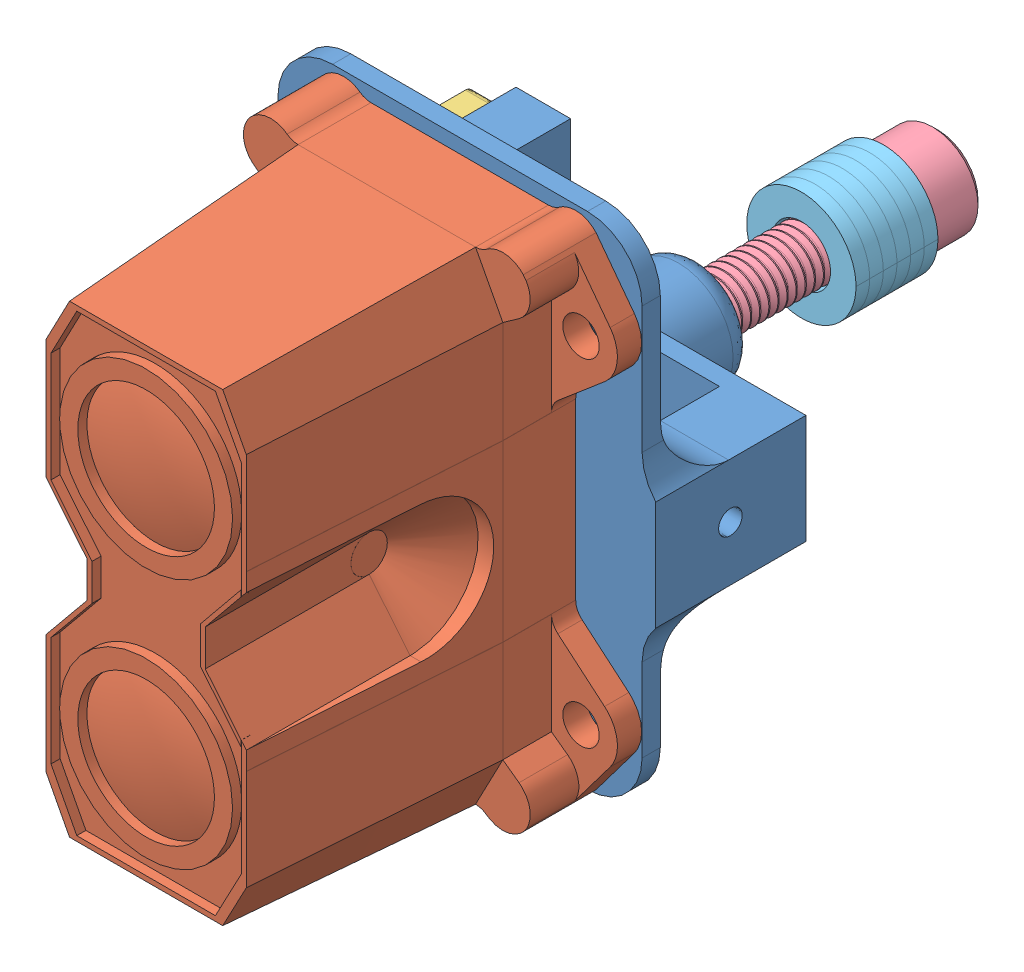
SolidWorks assembly lidar_assembly, configuration Default. Lengths in mm.
Overall size (46.37 55.51 87.17).
10 component instances, 5 part files, 7 mates.
Components (placement in the parent):
- lidar_mount-1: lidar_mount [Default] at (57.1287 41.2951 14.349) size (41.87 55 26.5)
- Garmin LIDAR-Lite V3HP-1: Garmin LIDAR-Lite V3HP [Default] at (77.1287 68.2951 16.3924) x (-1 0 0) z (0 1 0) size (44.51 34.67 55.01)
- SG90 - Micro Servo 9g - Tower Pro.1-2: SG90 - Micro Servo 9g - Tower Pro.1 [Peça] at (71.9287 71.6451 8.149) x (0 1 0) z (0 0 1) size (32.1 29.95 12.4)
- M6x30-1: M6x30 [Default] at (77.1287 66.3951 -36.151) x (0 0 1) z (-1 0 0) size (36.03 10 10)
- 9430109.stp-1: 9430109.stp [Default] at (77.1287 66.3951 -28.651) x (1 0 0) z (0 1 0) size (12 1.5 12)
- 9430109.stp-5: 9430109.stp [Default] at (77.1287 66.3951 -27.151) x (1 0 0) z (0 1 0) size (12 1.5 12)
- 9430109.stp-6: 9430109.stp [Default] at (77.1287 66.3951 -25.651) x (1 0 0) z (0 1 0) size (12 1.5 12)
- 9430109.stp-7: 9430109.stp [Default] at (77.1287 66.3951 -24.151) x (1 0 0) z (0 1 0) size (12 1.5 12)
- 9430109.stp-8: 9430109.stp [Default] at (77.1287 66.3951 -22.651) x (1 0 0) z (0 1 0) size (12 1.5 12)
- 9430109.stp-9: 9430109.stp [Default] at (77.1287 66.3951 -21.151) x (1 0 0) z (0 1 0) size (12 1.5 12)
Mates (geometry in assembly coordinates):
- Coincident1: coincident aligned: circle of lidar_mount-1; cylinder of Garmin LIDAR-Lite V3HP-1 through (61.1287 86.7951 16.3924) axis (0 0 1) radius 2
- Concentric2: concentric aligned: cylinder of lidar_mount-1 through (97.1287 57.7451 8.149) axis (-1 0 0) radius 0.8; cylinder of SG90 - Micro Servo 9g - Tower Pro.1-2 through (82.4787 57.7451 8.149) axis (-1 0 0) radius 1.1
- Coincident2: coincident anti-aligned: plane of lidar_mount-1 through (66.7787 41.2951 1.849) normal (-1 0 0); plane of SG90 - Micro Servo 9g - Tower Pro.1-2 through (66.7787 56.4451 13.399) normal (1 0 0)
- Coincident6: coincident anti-aligned: circle of lidar_mount-1; plane of M6x30-1 through (77.1287 66.3951 -0.151) normal (0 0 1)
- Concentric3: concentric aligned: circle of lidar_mount-1; circle of M6x30-1
- Coincident10: coincident anti-aligned: plane of M6x30-1 through (77.1287 69.3821 -30.151) normal (0 0 1); plane of 9430109.stp-1 through (77.1287 66.3951 -30.151) normal (0 0 -1)
- Concentric4: concentric anti-aligned: circle of M6x30-1; circle of 9430109.stp-1
